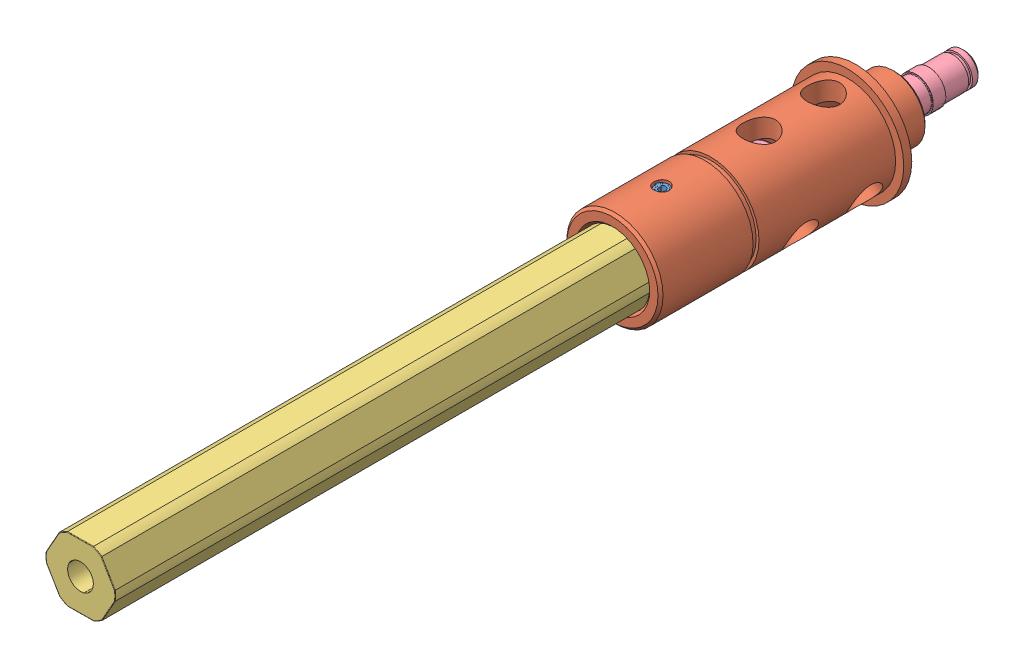
SolidWorks assembly 10-510 Short Shifter, configuration Default. Lengths in mm.
Overall size (22.23 22.23 174.73).
4 component instances, 4 part files, 2 mates.
Components (placement in the parent):
- 217-4098-005 Rev1_91612A226-1: 217-4098-005 Rev1_91612A226 [Default] at (0 0 46.2661) x (-0.144757 0 0.989467) z (0 -1 0) size (3.02 3.15 18.22)
- 217-4098-003 Rev2-1: 217-4098-003 Rev2 [Default] x (1 0 0) z (0 0 -1) size (22.23 22.23 55.94)
- 217-4099-002 Rev3-1: 217-4099-002 Rev3 [Default] at (0 0 53.467) x (0 0 1) z (0.999946 0.010384 0) size (130.09 12.73 14.67)
- 217-4098-004 Rev1-1: 217-4098-004 Rev1 [Default] at (0 0 26.9494) x (-0.895647 -0.444765 0) z (0 0 1) size (11.68 11.68 56)
Mates (geometry in assembly coordinates):
- Concentric3: concentric anti-aligned: circle of 217-4098-003 Rev2-1; cylinder of 217-4099-002 Rev3-1 through (0 0 30.9885) axis (0 0 1) radius 5.955
- Distance1: distance = 8.279 mm: cylinder of 217-4099-002 Rev3-1 through (-0.0661 6.3624 46.2661) axis (0.010384 -0.999946 0) radius 1.5; plane of 217-4098-003 Rev2-1 through (0 -9.5123 36.4871) normal (0 0 1)
